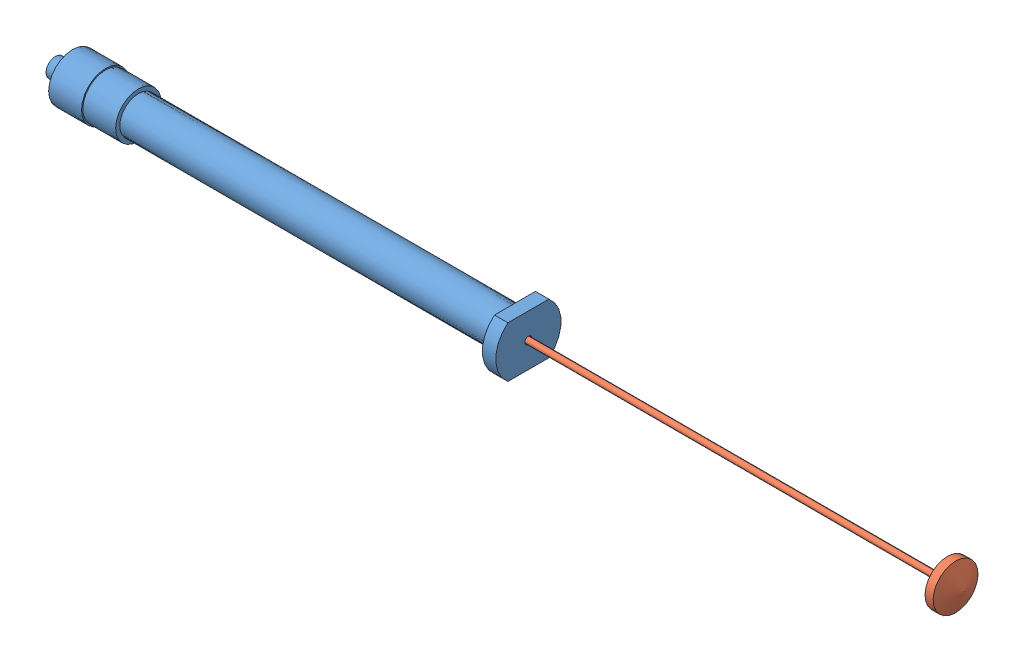
SolidWorks assembly 100_Microliter_Hamilton_Syringe_Asmbly, configuration Default. Lengths in mm.
Overall size (189.28 10.6 13.61).
2 component instances, 2 part files, 2 mates.
Components (placement in the parent):
- Hamilton_100Microliter_Syringe-1: Hamilton_100Microliter_Syringe [Default] at (44.0933 54.0947 70.0049) size (98.57 10.6 13.61)
- 100Microliter_Plunger-1: 100Microliter_Plunger [Default] at (134.6683 54.0947 70.0049) x (1 0 0) z (0 0.039404 0.999223) size (98.84 9.35 9.35)
Mates (geometry in assembly coordinates):
- Concentric1: concentric: circle of Hamilton_100Microliter_Syringe-1; circle of 100Microliter_Plunger-1
- Distance1: distance = 87.31 mm anti-aligned: plane of Hamilton_100Microliter_Syringe-1 through (93.3783 54.0947 63.1999) normal (1 0 0); plane of 100Microliter_Plunger-1 through (180.6883 54.7192 69.9802) normal (-1 0 0)
